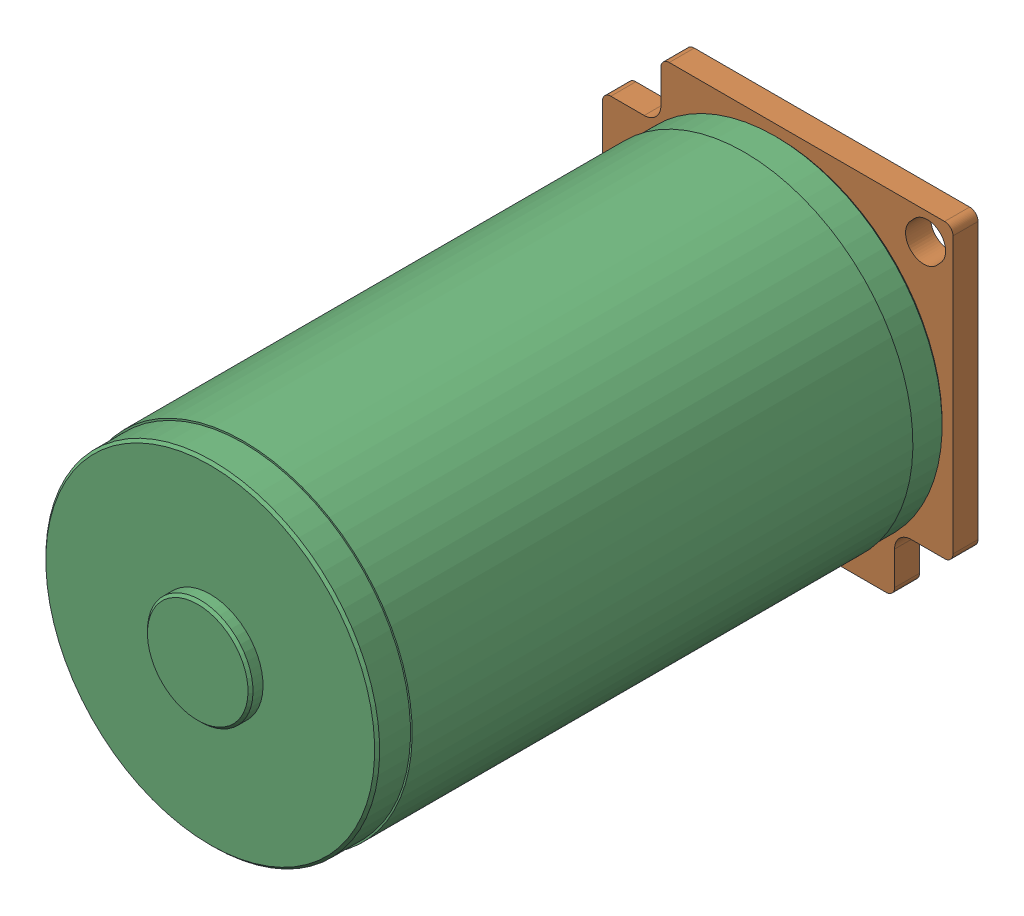
SolidWorks assembly 217-3564-000 Rev1_BAG_1, configuration Default. Lengths in mm.
Overall size (42 42 81.5).
3 component instances, 3 part files, 0 mates.
Components (placement in the parent):
- 217-2625-011 Rev1_2-1: 217-2625-011 Rev1_2 [Default] at (0 0 -5.25) x (1 0 0) z (0 -1 0) size (8.01 7.5 7.94)
- 217-2822-003 Rev4_1-1: 217-2822-003 Rev4_1 [Default] at (0 0 1.5) size (42 42 4.8)
- 217-3351_2-1: 217-3351_2 [Default] at (0 0 3) x (0 1 0) z (0 0 -1) size (40.4 40.4 81.5)
